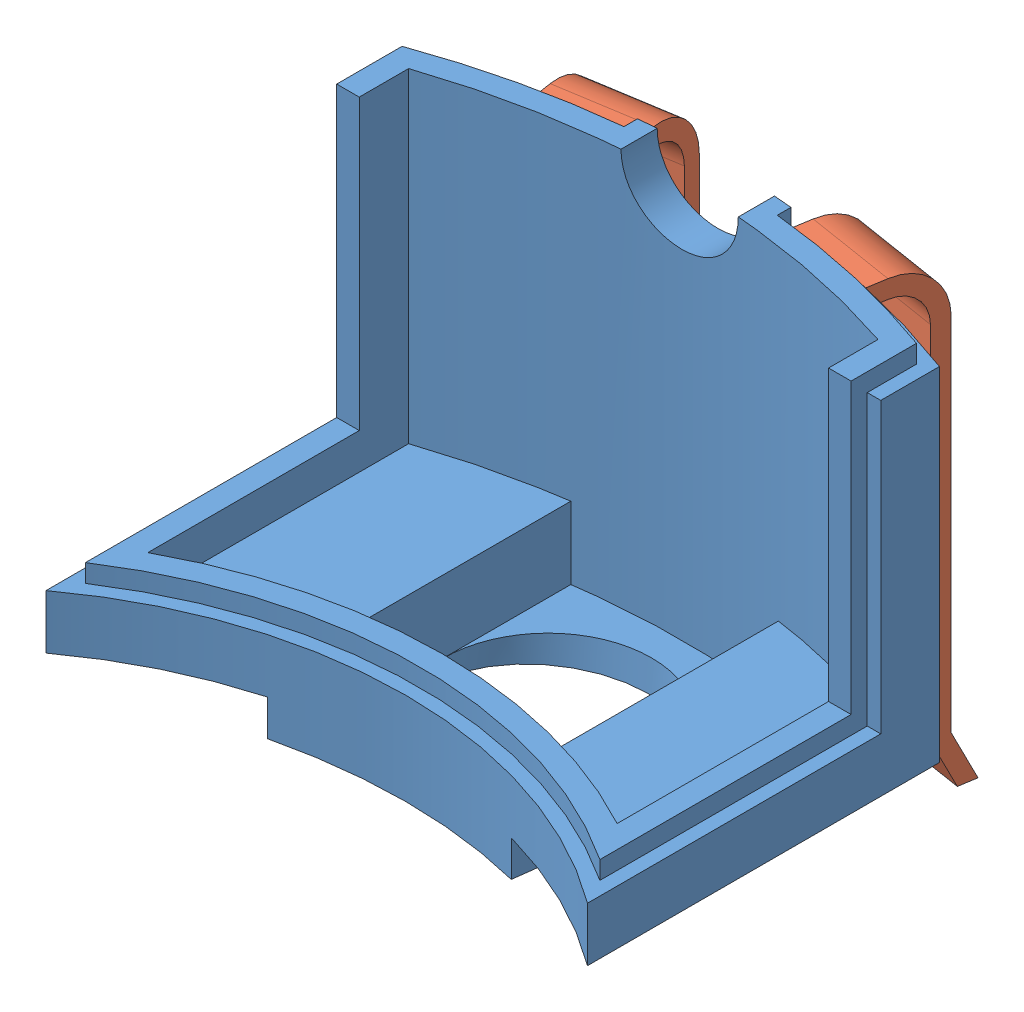
SolidWorks assembly Assem1, configuration Default. Lengths in mm.
Overall size (30 26.94 27.38).
3 component instances, 2 part files, 6 mates.
Components (placement in the parent):
- support_pir_part1_bis-1: support_pir_part1_bis [Default] at (-3.1542 0.369 40.9866) size (30 24.18 22.24)
- clips-1: clips [Default] at (-13.2005 -6.388 -5.8672) x (-0.158356 0 -0.987382) z (0.987382 0 -0.158356) size (5.43 25.76 5)
- clips-2: clips [Default] at (1.9552 -6.388 -6.659) x (0.158356 0 -0.987382) z (0.987382 0 0.158356) size (5.43 25.76 5)
Mates (geometry in assembly coordinates):
- Concentric1: concentric anti-aligned: cylinder of support_pir_part1_bis-1 through (-3.1542 2.369 40.9866) axis (0 -1 0) radius 42.5; cylinder of clips-1 through (-3.1542 -6.388 40.9866) axis (0 1 0) radius 42.5
- Coincident3: coincident aligned: plane of support_pir_part1_bis-1 through (-3.1542 19.369 40.9866) normal (0 1 0); plane of clips-1 through (-12.1944 19.369 0.4061) normal (0 1 0)
- Coincident5: coincident: line of support_pir_part1_bis-1 through (-7.4042 19.369 -1.3003) axis (0 1 0); plane of clips-1 through (-7.5742 16.3125 -2.3604) normal (0.987382 0 -0.158356)
- Concentric2: concentric: cylinder of support_pir_part1_bis-1 through (-3.1542 2.369 40.9866) axis (0 -1 0) radius 42.5; cylinder of clips-2 through (-3.1542 -6.388 40.9866) axis (0 1 0) radius 42.5
- Coincident6: coincident: plane of support_pir_part1_bis-1 through (-3.1542 19.369 40.9866) normal (0 1 0); plane of clips-2 through (0.9491 19.369 -0.3856) normal (0 1 0)
- Coincident7: coincident aligned: line of support_pir_part1_bis-1 through (1.0958 19.369 -1.3003) axis (0 1 0); line of clips-2 through (1.0958 18.369 -1.3003) axis (0 1 0)
